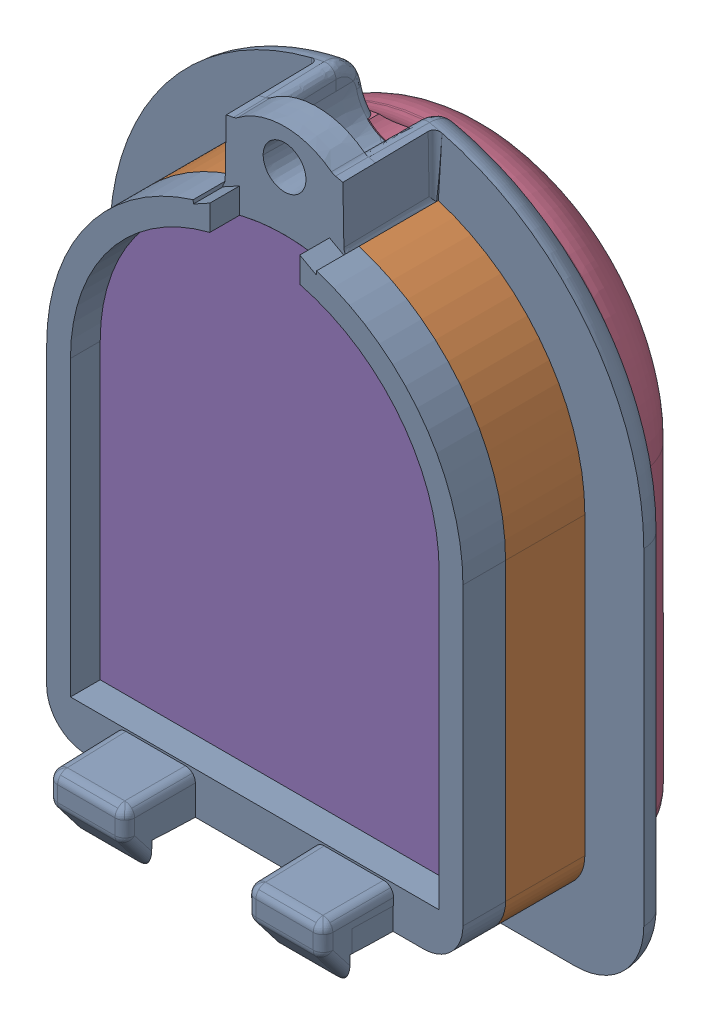
SolidWorks assembly Digit_4.2, configuration 默认. Lengths in mm.
Overall size (26.95 34.26 15.66).
5 component instances, 5 part files, 13 mates.
Components (placement in the parent):
- OriginBody-1: OriginBody [默认] at (-2.213 7.3799 -8.324) size (26.95 34.26 11.2)
- TransBody-1: TransBody [默认] at (-2.213 7.3799 -8.324) size (21 26.93 4)
- InsideSKin-2: InsideSKin [默认] at (-2.213 4.0799 -7.824) x (-1 0 0) z (0 0 -1) size (18.6 25.2 4.2)
- outSkin-1: outSkin [默认] at (-2.213 4.0799 -7.824) x (-1 0 0) z (0 0 -1) size (21.8 28.5 5)
- Lens-1: Lens [默认] at (-2.213 7.3799 -7.824) size (18.6 25.2 5.65)
Mates (geometry in assembly coordinates):
- 重合1: coincident anti-aligned: plane of OriginBody-1 through (-2.213 7.3799 -6.824) normal (0 0 1); plane of TransBody-1 through (7.137 -9.7124 -6.824) normal (0 0 -1)
- 同心1: concentric aligned: cylinder of OriginBody-1 through (-2.213 7.3799 -0.674) axis (0 0 -1) radius 10.5; cylinder of TransBody-1 through (-2.213 7.3799 -0.674) axis (0 0 -1) radius 10.5
- 重合2: coincident aligned: plane of OriginBody-1 through (8.287 7.3799 -0.674) normal (1 0 0); plane of TransBody-1 through (8.287 7.3799 -0.674) normal (1 0 0)
- 重合3: coincident anti-aligned: plane of TransBody-1 through (-2.213 -8.5201 48.523) normal (0 1 0); plane of Lens-1 through (-11.513 -8.5201 -2.174) normal (0 -1 0)
- 同心2: concentric aligned: cylinder of TransBody-1 through (-2.213 7.3799 48.523) axis (0 0 -1) radius 9.3; cylinder of Lens-1 through (-2.213 7.3799 -2.174) axis (0 0 -1) radius 9.3
- 平行2: parallel aligned: plane of InsideSKin-2 through (-11.013 -8.5201 -12.024) normal (0 -1 0); plane of outSkin-1 through (-11.013 -9.3201 -12.024) normal (0 -1 0)
- 距离1: distance = 0.5 mm anti-aligned: plane of OriginBody-1 through (-2.2735 3.9424 -8.324) normal (0 0 -1); plane of outSkin-1 through (-11.013 -8.0201 -7.824) normal (0 0 1)
- 同心5: concentric aligned: cone of OriginBody-1 through (-2.213 19.6299 -3.824) axis (0 0 1); cylinder of outSkin-1 through (-2.213 19.6299 -17.824) axis (0 0 1) radius 2.0018
- 同心6: concentric aligned: cone of OriginBody-1 through (-2.213 19.6299 -3.824) axis (0 0 1); cylinder of outSkin-1 through (-2.213 19.6299 -17.824) axis (0 0 1) radius 2.0018
- 重合10: coincident anti-aligned: plane of InsideSKin-2 through (-11.013 -8.0201 -7.824) normal (0 0 1); plane of Lens-1 through (-2.213 7.3799 -7.824) normal (0 0 -1)
- 同心8: concentric anti-aligned: circle of InsideSKin-2; circle of Lens-1
- 同心9: concentric aligned: cone of OriginBody-1 through (-2.213 19.6299 -3.824) axis (0 0 1); cylinder of outSkin-1 through (-2.213 19.6299 -17.824) axis (0 0 1) radius 2.0018
- 重合11: coincident aligned: plane of OriginBody-1 through (-2.213 7.3799 -2.174) normal (0 0 1); plane of Lens-1 through (-2.213 7.3799 -2.174) normal (0 0 1)
